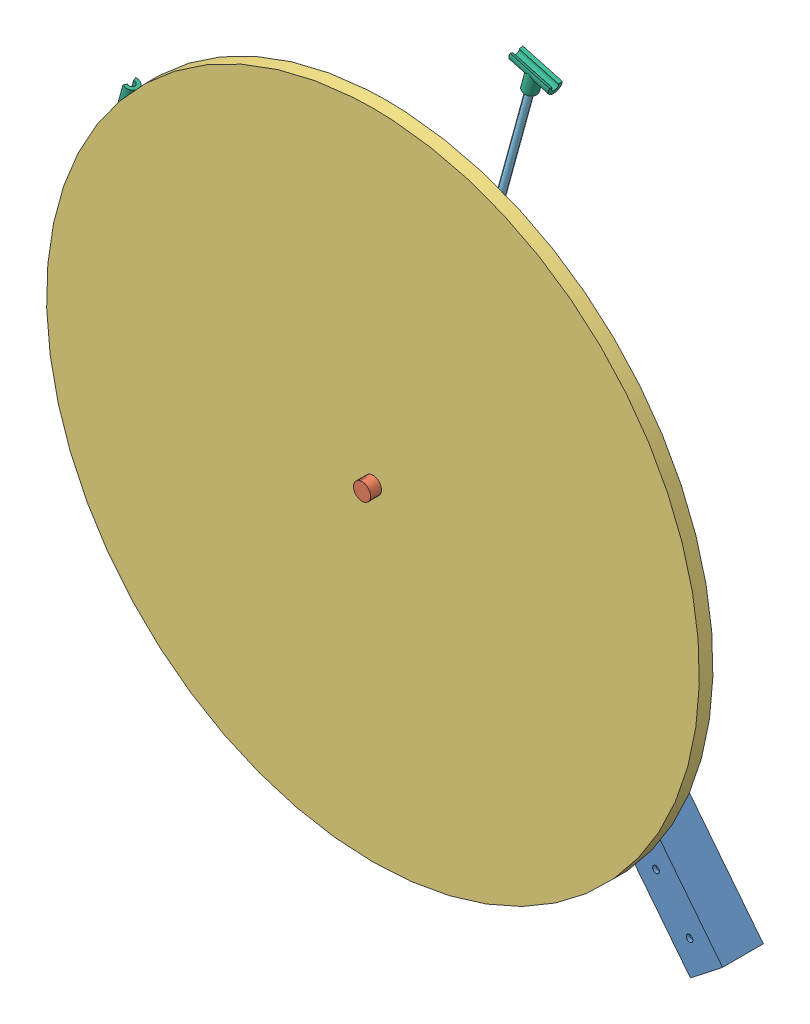
SolidWorks assembly Arm Assembly2, configuration Default. Lengths in mm.
Overall size (320.82 347.5 58.75).
9 component instances, 6 part files, 7 mates.
Components (placement in the parent):
- Arm-1: Arm [Default] at (163.5465 -14.9048 159.1998) size (145.36 177.44 19.05)
- Motor-1: Motor [Default] at (-40.2614 179.8597 178.2498) x (0.175426 -0.984493 0) z (-0.984493 -0.175426 0) size (254 42.2 254)
- spinningProp-1: spinningProp [Default] at (-40.2614 179.8597 212.8398) x (1 0 0) z (0 1 0) size (304.8 6.35 304.8) (hidden)
- wirePropMount-1: wirePropMount [Default] at (-69.6606 195.1604 149.8229) x (0.785792 0.61849 0) z (0.61849 -0.785792 0) size (232.44 15.88 157)
  - rodMount1-1: rodMount1 [Default] at (13.6383 18.9019 15.2057) size (15.88 15.88 33.34)
  - rod-1: rod [Default] at (13.6383 18.9019 15.2057) x (0.656472 0.577129 -0.485764) z (-0.594823 0 -0.803857) size (3.17 3.17 152.4)
  - rod-2: rod [Default] at (136.1461 18.9019 -75.4453) x (-0.310525 -0.852917 -0.41965) z (-0.803857 0 0.594823) size (3.17 3.17 152.4)
  - gaurdBracket-1: gaurdBracket [Default] at (-78.9012 18.9019 -109.8543) x (0.803857 0 -0.594823) z (0.594823 0 0.803857) size (19.05 6.35 10.61)
  - gaurdBracket-2: gaurdBracket [Default] at (138.6984 18.9019 -77.3339) x (0.594823 0 0.803857) z (-0.803857 0 0.594823) size (19.05 6.35 10.61)
Mates (geometry in assembly coordinates):
- Concentric4: concentric anti-aligned: cylinder of Motor-1 through (-40.2614 179.8597 217.9498) axis (0 0 -1) radius 4; cylinder of spinningProp-1 through (-40.2614 179.8597 206.4898) axis (0 0 1) radius 3.175
- Distance1: distance = 2.54 mm anti-aligned: plane of Motor-1 through (-40.2614 179.8597 203.9498) normal (0 0 1); plane of spinningProp-1 through (-40.2614 179.8597 206.4898) normal (0 0 -1)
- Coincident1: coincident anti-aligned: plane of Arm-1 through (163.5465 -14.9048 178.2498) normal (0 0 1); plane of Motor-1 through (-40.2614 179.8597 178.2498) normal (0 0 -1)
- Concentric5: concentric aligned: cylinder of Arm-1 through (-40.2614 179.8597 175.7098) axis (0 0 1) radius 3.25; cylinder of Motor-1 through (-40.2614 179.8597 175.7498) axis (0 0 1) radius 3
- Coincident2: coincident anti-aligned: plane of Arm-1 through (163.5465 -14.9048 176.6623) normal (0 0 -1); plane of wirePropMount-1/rodMount1-1 through (-40.0667 166.7787 176.6623) normal (0 0 1)
- Coincident3: coincident anti-aligned: plane of Arm-1 through (-55.7764 186.7378 178.2498) normal (0.785792 0.61849 0); plane of wirePropMount-1/rodMount1-1 through (-40.0667 166.7787 176.6623) normal (-0.785792 -0.61849 0)
- Coincident4: coincident aligned: plane of Arm-1 through (-57.0238 185.756 178.2498) normal (-0.61849 0.785792 0); plane of wirePropMount-1/rodMount1-1 through (-49.5392 191.6471 168.7248) normal (-0.61849 0.785792 0)
